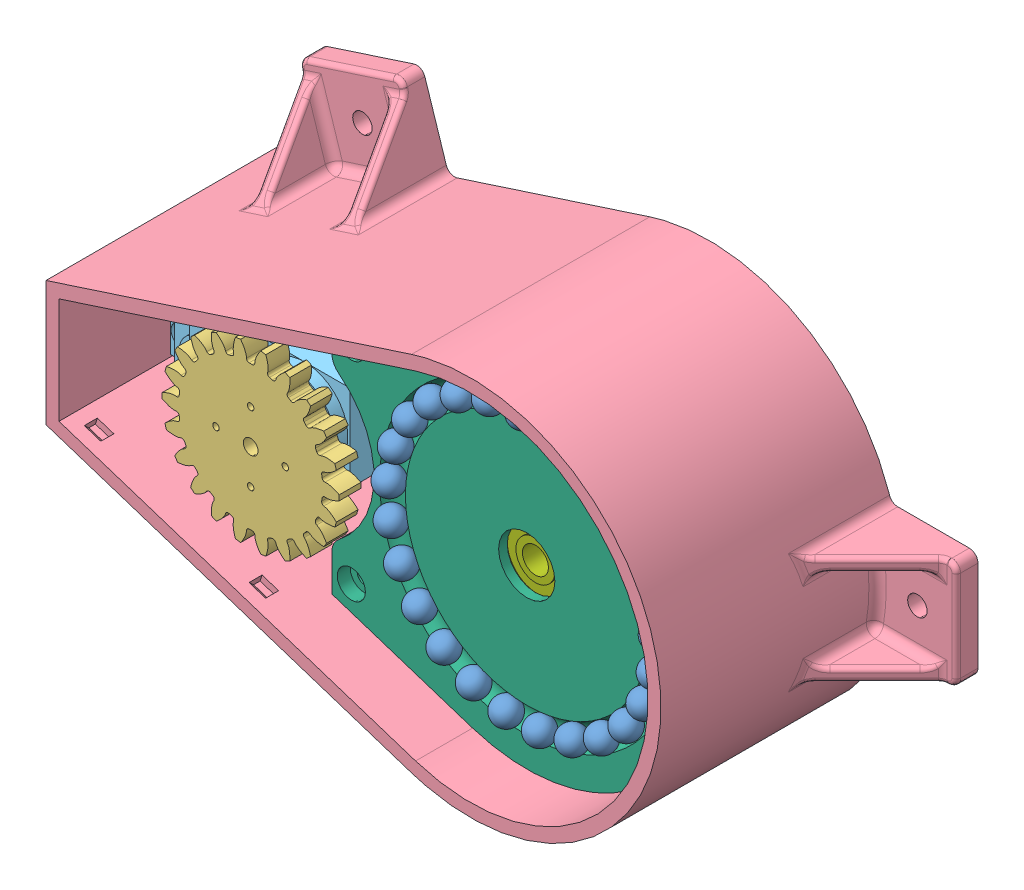
SolidWorks assembly Base, configuration Predeterminado. Lengths in mm.
Overall size (160.19 90.57 55).
31 component instances, 7 part files, 0 mates.
Components (placement in the parent):
- 020 ball.step-1: 020 ball.step [Predeterminado] at (29.3993 9.5524 42.8783) x (0.309017 -0.951057 0) z (0 0 1) size (6 6 6)
- 020 ball.step-2: 020 ball.step [Predeterminado] at (-27.9703 -13.1618 42.8783) x (-0.425779 0.904827 0) z (0 0 1) size (6 6 6)
- MG946R_piattelo.step-1: MG946R_piattelo.step [Predeterminado] at (-56.3 0 45.9) size (20.5 20.5 5.7)
- 020 ball.step-3: 020 ball.step [Predeterminado] at (18.1698 -25.0086 42.8783) x (-0.809017 -0.587785 0) z (0 0 1) size (6 6 6)
- 020 ball.step-4: 020 ball.step [Predeterminado] at (-11.3796 -28.7415 42.8783) x (-0.929776 0.368125 0) z (0 0 1) size (6 6 6)
- 020 ball.step-5: 020 ball.step [Predeterminado] at (7.6876 29.9411 42.8783) x (0.968583 -0.24869 0) z (0 0 1) size (6 6 6)
- 010_gearservo.step-1: 010_gearservo.step [Predeterminado] at (-56.3 -0.75 44.45) x (0 1 0) z (-1 0 0) size (40.71 5.06 40.95)
- 020 ball.step-6: 020 ball.step [Predeterminado] at (-30.3647 -5.7924 42.8783) x (-0.187381 0.982287 0) z (0 0 1) size (6 6 6)
- 020 ball.step-7: 020 ball.step [Predeterminado] at (-23.8183 -19.7042 42.8783) x (-0.637424 0.770513 0) z (0 0 1) size (6 6 6)
- 020 ball.step-8: 020 ball.step [Predeterminado] at (-29.3993 9.5524 42.8783) x (0.309017 0.951057 0) z (0 0 1) size (6 6 6)
- 020 ball.step-9: 020 ball.step [Predeterminado] at (14.8921 27.0886 42.8783) x (0.876307 -0.481754 0) z (0 0 1) size (6 6 6)
- 020 ball.step-10: 020 ball.step [Predeterminado] at (23.8183 -19.7042 42.8783) x (-0.637424 -0.770513 0) z (0 0 1) size (6 6 6)
- 020 ball.step-11: 020 ball.step [Predeterminado] at (-3.8743 -30.6685 42.8783) x (-0.992115 0.125333 0) z (0 0 1) size (6 6 6)
- 020 ball.step-12: 020 ball.step [Predeterminado] at (-18.1698 -25.0086 42.8783) x (-0.809017 0.587785 0) z (0 0 1) size (6 6 6)
- 020 ball.step-13: 020 ball.step [Predeterminado] at (30.8513 1.941 42.8783) x (0.062791 -0.998027 0) z (0 0 1) size (6 6 6)
- 020 ball.step-14: 020 ball.step [Predeterminado] at (30.3647 -5.7924 42.8783) x (-0.187381 -0.982287 0) z (0 0 1) size (6 6 6)
- 020 ball.step-15: 020 ball.step [Predeterminado] at (-14.8921 27.0886 42.8783) x (0.876307 0.481754 0) z (0 0 1) size (6 6 6)
- 012_base.step-1: 012_base.step [Predeterminado] at origin size (160.19 90.57 55)
- 020 ball.step-16: 020 ball.step [Predeterminado] at (3.8743 -30.6685 42.8783) x (-0.992115 -0.125333 0) z (0 0 1) size (6 6 6)
- 020 ball.step-17: 020 ball.step [Predeterminado] at (11.3796 -28.7415 42.8783) x (-0.929776 -0.368125 0) z (0 0 1) size (6 6 6)
- MG946R.step-1: MG946R.step [Predeterminado] at (-66.05 0 8.5) size (54.5 20 43.3)
- 020 ball.step-18: 020 ball.step [Predeterminado] at (27.9703 -13.1618 42.8783) x (-0.425779 -0.904827 0) z (0 0 1) size (6 6 6)
- 020 ball.step-19: 020 ball.step [Predeterminado] at (26.1001 16.5636 42.8783) x (0.535827 -0.844328 0) z (0 0 1) size (6 6 6)
- 020 ball.step-20: 020 ball.step [Predeterminado] at (0 30.9123 42.8783) size (6 6 6)
- 020 ball.step-21: 020 ball.step [Predeterminado] at (-21.1609 22.5341 42.8783) x (0.728969 0.684547 0) z (0 0 1) size (6 6 6)
- 020 ball.step-22: 020 ball.step [Predeterminado] at (-7.6876 29.9411 42.8783) x (0.968583 0.24869 0) z (0 0 1) size (6 6 6)
- 020 ball.step-23: 020 ball.step [Predeterminado] at (-26.1001 16.5636 42.8783) x (0.535827 0.844328 0) z (0 0 1) size (6 6 6)
- 013 lower base.step-1: 013 lower base.step [Predeterminado] at (0 0 34) size (85.8 81.6 8)
- 020 ball.step-24: 020 ball.step [Predeterminado] at (-30.8513 1.941 42.8783) x (0.062791 0.998027 0) z (0 0 1) size (6 6 6)
- 606.step-1: 606.step [Predeterminado] at (0 0 37) size (17 17 6)
- 020 ball.step-25: 020 ball.step [Predeterminado] at (21.1609 22.5341 42.8783) x (0.728969 -0.684547 0) z (0 0 1) size (6 6 6)
